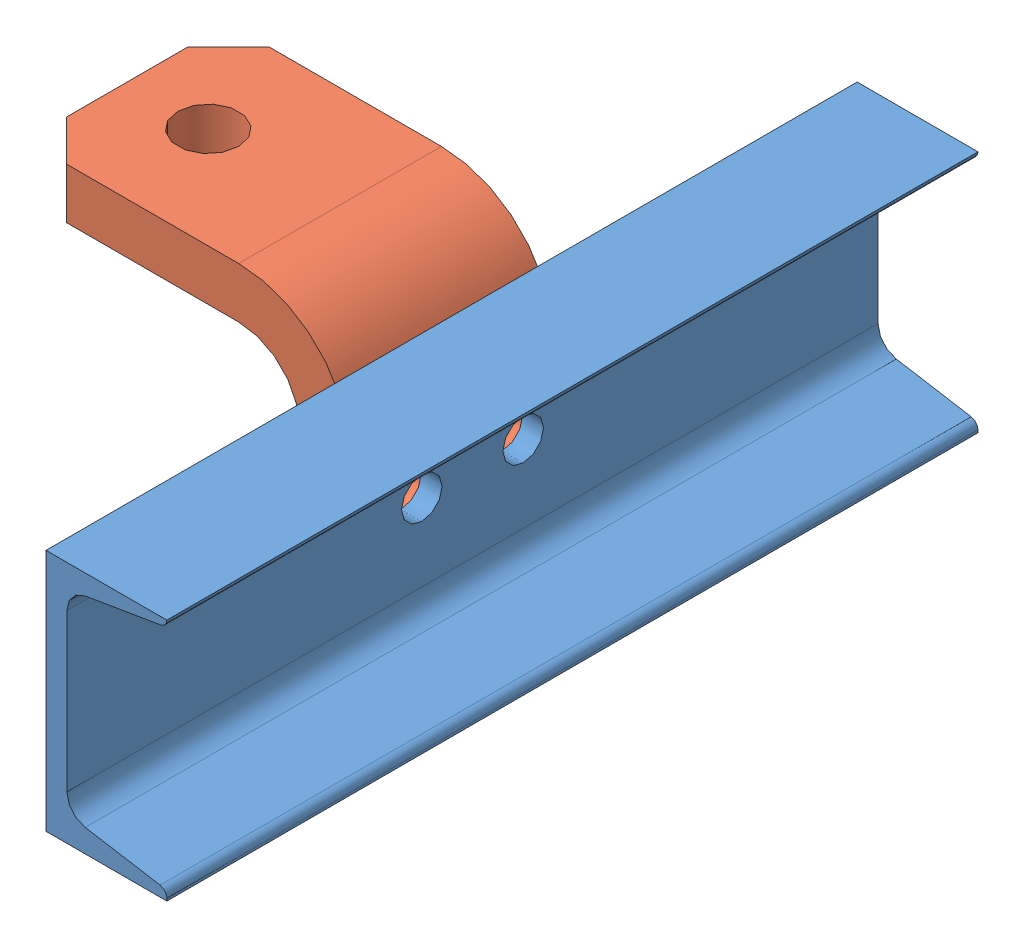
SolidWorks assembly Hitch-Channel Assembly 7-3, configuration Default. Lengths in mm.
Overall size (139.45 88.9 254).
2 component instances, 2 part files, 3 mates.
Components (placement in the parent):
- Hitch Channel 7-3-1: Hitch Channel 7-3 [Default] at origin size (37.85 76.2 254)
- Hitch 7-3-1: Hitch 7-3 [Default] at (-76.2 34.925 0) x (-1 0 0) z (0 0 -1) size (101.6 76.2 63.5)
Mates (geometry in assembly coordinates):
- Coincident1: coincident: plane of Hitch Channel 7-3-1 through (0 -38.1 127) normal (-1 0 0); plane of Hitch 7-3-1 through (0 -25.4 -31.75) normal (1 0 0)
- Coincident2: coincident: line of Hitch Channel 7-3-1 through (6.5532 0 15.875) axis (-1 0 0); line of Hitch 7-3-1 through (0 0 15.875) axis (-1 0 0)
- Coincident3: coincident aligned: line of Hitch Channel 7-3-1 through (6.5532 0 -15.875) axis (-1 0 0); line of Hitch 7-3-1 through (0 0 -15.875) axis (-1 0 0)
